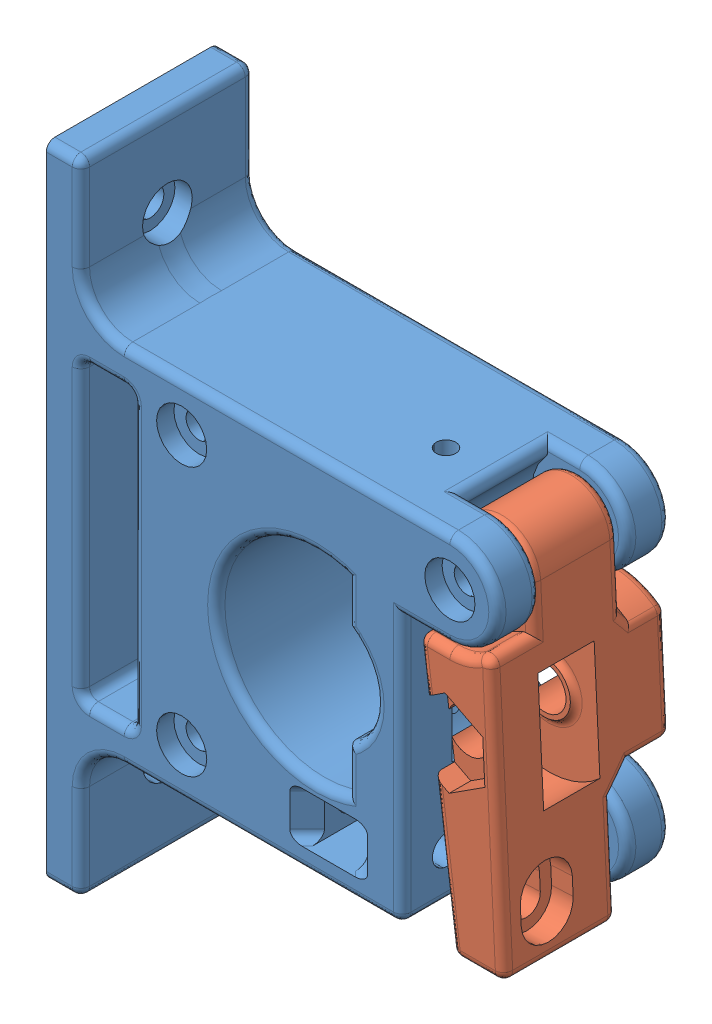
SolidWorks assembly extruder_dd, configuration Default. Lengths in mm.
Overall size (52.91 74 20.09).
2 component instances, 2 part files, 4 mates.
Components (placement in the parent):
- extruder_dd_body-2: extruder_dd_body [Default] at origin size (52.15 74 20.09)
- extruder_dd_hinge-1: extruder_dd_hinge [Default] at (0 0 5) size (10.76 41 20.07)
Mates (geometry in assembly coordinates):
- InPlace1: in place: plane of extruder_dd_body-2 through (0 0 5) normal (0 0 1); plane of extruder_dd_hinge-1 through (0 0 5) normal (0 0 1); moOrthogonalPlaneRef_w of extruder_dd_body-2 through (0 0 5) normal (0 0 1); plane of extruder_dd_hinge-1 through (0 0 5) normal (0 1 0); plane of extruder_dd_body-2 through (0 0 5) normal (0 0 1); plane of extruder_dd_hinge-1 through (0 0 5) normal (1 0 0); plane of extruder_dd_body-2 through (0 0 5) normal (0 0 1); unknown of extruder_dd_hinge-1
- Coincident3: coincident aligned: plane of extruder_dd_body-2; plane of extruder_dd_hinge-1
- Coincident4: coincident aligned: moOrthogonalPlaneRef_w of extruder_dd_body-2 through (0 0 5) normal (0 1 0); plane of extruder_dd_hinge-1 through (0 0 5) normal (0 1 0)
- Coincident5: coincident anti-aligned: moOrthogonalPlaneRef_w of extruder_dd_body-2 through (0 0 5) normal (-1 0 0); plane of extruder_dd_hinge-1 through (0 0 5) normal (1 0 0)
